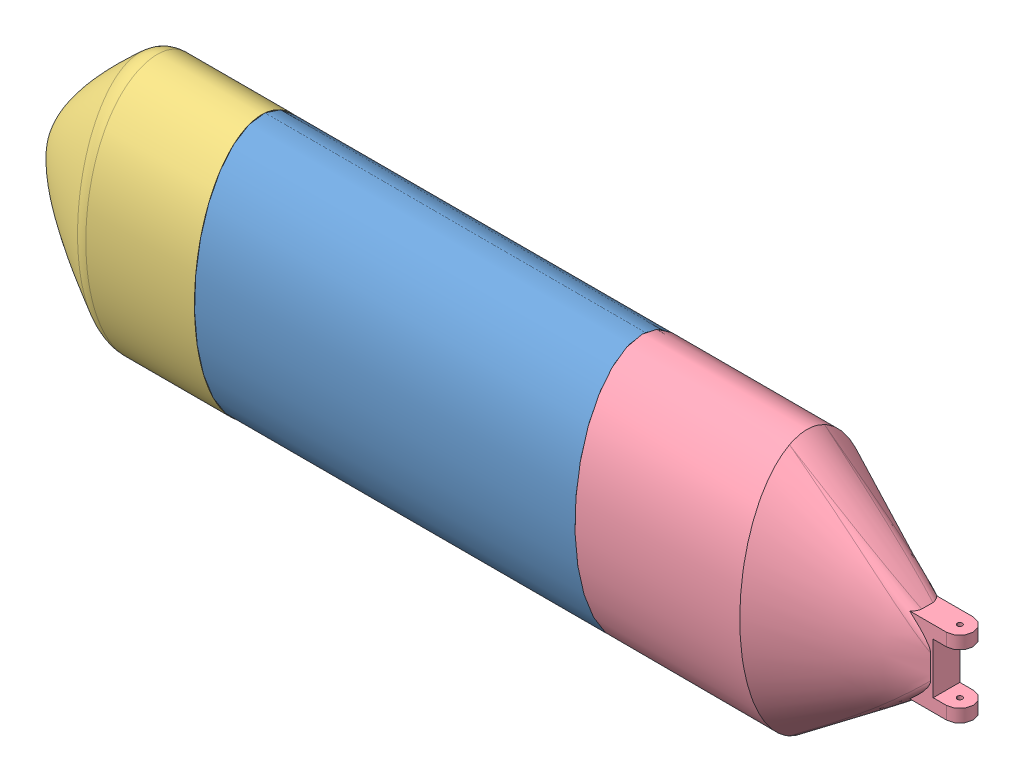
SolidWorks assembly Ass-y without tail, configuration По умолчанию. Lengths in mm.
Overall size (726 226.73 125.67).
5 component instances, 4 part files, 12 mates.
Components (placement in the parent):
- Cylinder-1: Cylinder [По умолчанию] at origin size (300 206 106)
- Porshen-1: Porshen [По умолчанию] at (10 0 0) x (0 0 -1) z (1 0 0) size (92 192 10)
- Porshen-2: Porshen [По умолчанию] at (280 0 0) x (0 0 -1) z (1 0 0) size (92 192 10)
- Nose-1: Nose [По умолчанию] at (10 0 0) x (-1 0 0) z (0 0 -1) size (175 226.73 125.67)
- Tail_Mount-2: Tail_Mount [По умолчанию] at (290 0 0) size (271 209.01 123.28)
Mates (geometry in assembly coordinates):
- Расстояние1: distance = 10 mm aligned: plane of Cylinder-1 through (0 0 0) normal (-1 0 0); plane of Porshen-1 through (10 0 0) normal (-1 0 0)
- Расстояние2: distance = 10 mm aligned: plane of Porshen-2 through (290 0 0) normal (1 0 0); plane of Cylinder-1 through (300 0 0) normal (1 0 0)
- Совпадение7: coincident anti-aligned: plane of Cylinder-1 through (0 0 0) normal (0 0 1); plane of Porshen-1 through (10 0 0) normal (0 0 -1)
- Совпадение8: coincident aligned: plane of Cylinder-1 through (0 0 0) normal (0 1 0); plane of Porshen-1
- Совпадение9: coincident aligned: plane of Cylinder-1 through (0 0 0) normal (0 1 0); plane of Porshen-2
- Совпадение10: coincident anti-aligned: plane of Cylinder-1 through (0 0 0) normal (0 0 1); plane of Porshen-2 through (280 0 0) normal (0 0 -1)
- Совпадение14: coincident anti-aligned: plane of Cylinder-1 through (0 0 0) normal (-1 0 0); plane of Nose-1 through (0 0 0) normal (1 0 0)
- Совпадение15: coincident aligned: plane of Cylinder-1 through (0 0 0) normal (0 1 0); plane of Nose-1
- Совпадение16: coincident anti-aligned: plane of Cylinder-1 through (0 0 0) normal (0 0 1); plane of Nose-1 through (10 0 0) normal (0 0 -1)
- Совпадение20: coincident anti-aligned: plane of Cylinder-1 through (300 0 0) normal (1 0 0); plane of Tail_Mount-2 through (300 0 0) normal (-1 0 0)
- Совпадение21: coincident aligned: plane of Cylinder-1 through (0 0 0) normal (0 1 0); plane of Tail_Mount-2 through (290 0 0) normal (0 1 0)
- Совпадение22: coincident aligned: plane of Tail_Mount-2 through (290 0 0) normal (0 0 1); plane of assembly through (0 0 0) normal (0 0 1)
